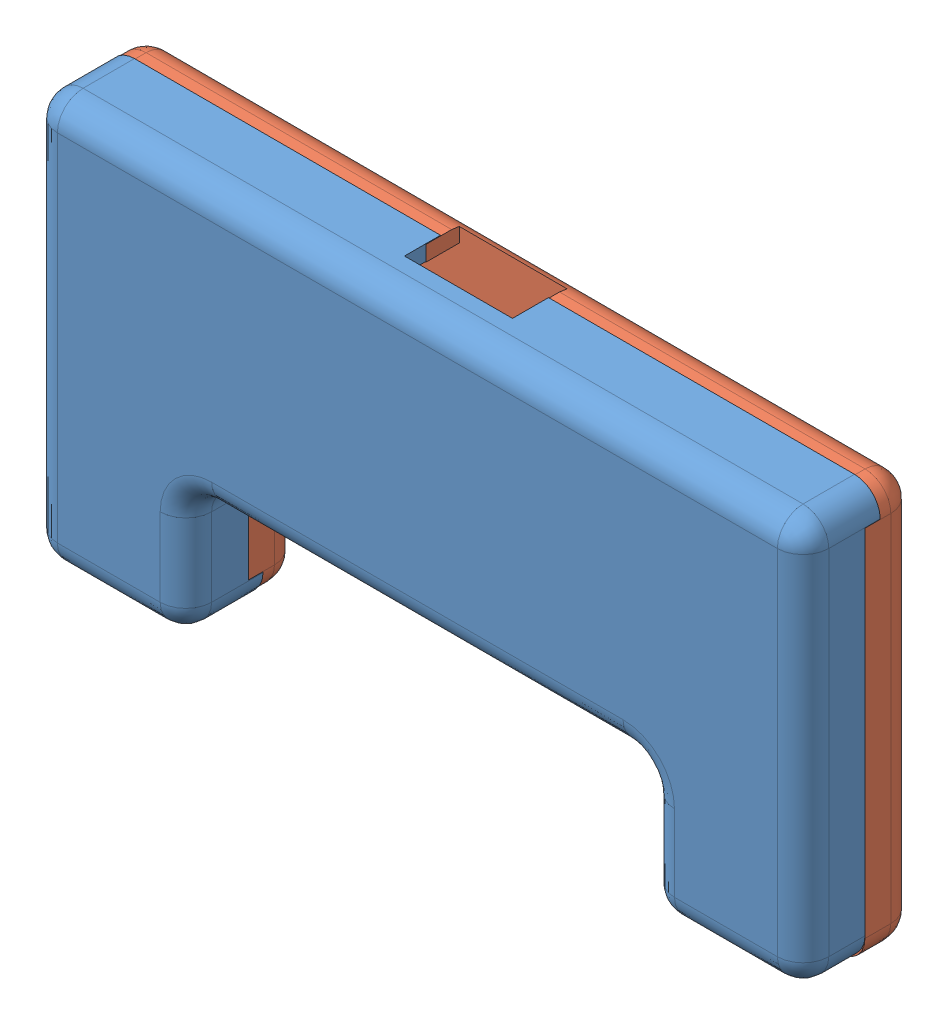
SolidWorks assembly Assem1, configuration Default. Lengths in mm.
Overall size (150.02 79.18 22.26).
2 component instances, 2 part files, 0 mates.
Components (placement in the parent):
- Part1-1: Part1 [Default] at (27.9626 117.6829 103.157) size (150 79.06 15)
- Part2-1: Part2 [Default] at (28.2386 78.166 103.0048) x (-0.999999 0 -0.001397) z (0.001397 0 -0.999999) size (150 79.06 10.04)
